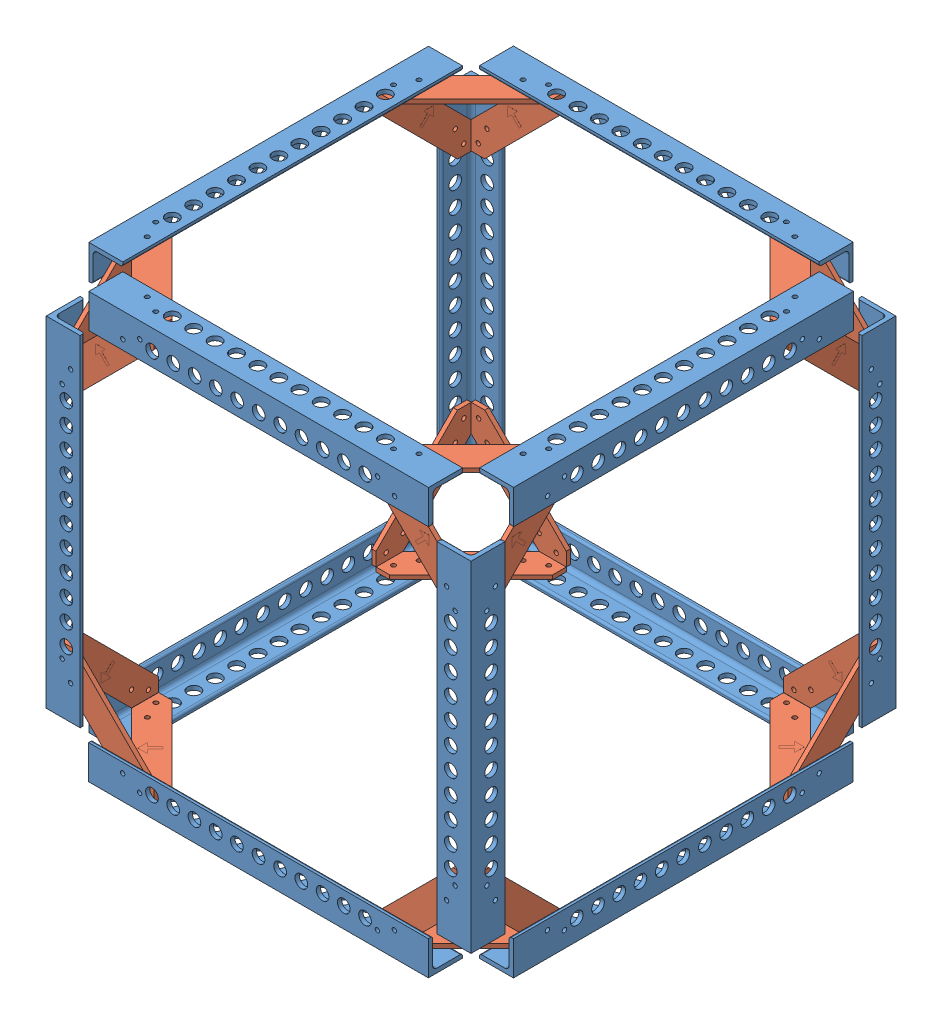
SolidWorks assembly Proof of Concept CAD 2 - Min Brackets, configuration Default. Lengths in mm.
Overall size (317.63 317.62 317.63).
38 component instances, 2 part files, 46 mates.
Components (placement in the parent):
- test assemby 1-1: test assemby 1 [Default] at (189.8318 11.2658 54.9643) size (317.51 25.4 317.63)
  - MOD Al L rod-4: MOD Al L rod [8982K401] at (158.011 130.5289 151.3983) size (25.4 25.4 254)
  - MOD Al L rod-5: MOD Al L rod [8982K401] at (11.9531 130.5289 5.2213) x (0 0 -1) z (1 0 0) size (25.4 25.4 254)
  - draft bracket-1: draft bracket [Default] at (164.361 121.0039 -1.0017) size (71.12 3.2 71.12)
  - MOD Al L rod-7: MOD Al L rod [8982K401] at (11.834 130.5289 297.4562) x (0 0 1) z (-1 0 0) size (25.4 25.4 254)
  - draft bracket-3: draft bracket [Default] at (164.234 121.0039 303.8062) x (0 0 1) z (-1 0 0) size (71.12 3.2 71.12)
  - MOD Al L rod-9: MOD Al L rod [8982K401] at (-134.0969 130.5289 151.2713) x (-1 0 0) z (0 0 -1) size (25.4 25.4 254)
  - draft bracket-6: draft bracket [Default] at (-140.4469 121.0039 -1.1287) x (0 0 -1) z (1 0 0) size (71.12 3.2 71.12)
  - draft bracket-7: draft bracket [Default] at (-140.4469 121.0039 303.6713) x (-1 0 0) z (0 0 -1) size (71.12 3.2 71.12)
- MOD Al L rod-1: MOD Al L rod [8982K401] at (55.6237 287.8447 352.4206) x (-1 0 0) z (0 -1 0) size (25.4 25.4 254)
- draft bracket-2: draft bracket [Default] at (49.2737 135.4447 361.9456) x (0 -1 0) z (1 0 0) size (71.12 3.2 71.12)
- draft bracket-3: draft bracket [Default] at (46.2099 135.5717 358.6357) x (0 0 1) z (0 1 0) size (71.12 3.2 71.12)
- draft bracket-4: draft bracket [Default] at (354.1928 135.4526 361.9456) x (1 0 0) z (0 1 0) size (71.12 3.2 71.12)
- draft bracket-5: draft bracket [Default] at (357.3678 135.4447 358.7706) x (0 -1 0) z (0 0 -1) size (71.12 3.2 71.12)
- MOD Al L rod-2: MOD Al L rod [8982K401] at (347.8428 287.8447 352.4206) x (0 0 1) z (0 -1 0) size (25.4 25.4 254)
- draft bracket-6: draft bracket [Default] at (49.3849 135.4447 50.6607) x (-1 0 0) z (0 1 0) size (71.12 3.2 71.12)
- draft bracket-7: draft bracket [Default] at (46.2099 135.4447 53.8357) x (0 -1 0) z (0 0 1) size (71.12 3.2 71.12)
- MOD Al L rod-3: MOD Al L rod [8982K401] at (55.7349 287.8447 60.1857) x (0 0 -1) z (0 -1 0) size (25.4 25.4 254)
- draft bracket-10: draft bracket [Default] at (357.3678 135.4447 53.8357) x (0 0 -1) z (0 1 0) size (71.12 3.2 71.12)
- draft bracket-11: draft bracket [Default] at (354.1928 135.4447 50.6607) x (0 -1 0) z (-1 0 0) size (71.12 3.2 71.12)
- MOD Al L rod-5: MOD Al L rod [8982K401] at (347.8428 287.8447 60.1857) x (1 0 0) z (0 -1 0) size (25.4 25.4 254)
- test assemby 1-2: test assemby 1 [Default] at (189.8397 564.5428 357.6419) x (1 0 0) z (0 0 -1) size (317.51 25.4 317.63)
  - MOD Al L rod-4: MOD Al L rod [8982K401] at (158.011 130.5289 151.3983) size (25.4 25.4 254)
  - MOD Al L rod-5: MOD Al L rod [8982K401] at (11.9531 130.5289 5.2213) x (0 0 -1) z (1 0 0) size (25.4 25.4 254)
  - draft bracket-1: draft bracket [Default] at (164.361 121.0039 -1.0017) size (71.12 3.2 71.12)
  - MOD Al L rod-7: MOD Al L rod [8982K401] at (11.834 130.5289 297.4562) x (0 0 1) z (-1 0 0) size (25.4 25.4 254)
  - draft bracket-3: draft bracket [Default] at (164.234 121.0039 303.8062) x (0 0 1) z (-1 0 0) size (71.12 3.2 71.12)
  - MOD Al L rod-9: MOD Al L rod [8982K401] at (-134.0969 130.5289 151.2713) x (-1 0 0) z (0 0 -1) size (25.4 25.4 254)
  - draft bracket-6: draft bracket [Default] at (-140.4469 121.0039 -1.1287) x (0 0 -1) z (1 0 0) size (71.12 3.2 71.12)
  - draft bracket-7: draft bracket [Default] at (-140.4469 121.0039 303.6713) x (-1 0 0) z (0 0 -1) size (71.12 3.2 71.12)
- draft bracket-13: draft bracket [Default] at (354.1928 440.2368 358.7706) x (1 0 0) z (0 -1 0) size (71.12 3.2 71.12)
- draft bracket-14: draft bracket [Default] at (354.1928 440.2526 358.6436) x (0 1 0) z (0 0 -1) size (71.12 3.2 71.12)
- draft bracket-15: draft bracket [Default] at (49.2737 440.2368 358.7706) x (0 0 1) z (0 -1 0) size (71.12 3.2 71.12)
- draft bracket-16: draft bracket [Default] at (49.2737 440.3638 358.7706) x (0 1 0) z (1 0 0) size (71.12 3.2 71.12)
- draft bracket-17: draft bracket [Default] at (49.2816 440.3638 50.6607) x (0 1 0) z (1 0 0) size (71.12 3.2 71.12)
- draft bracket-18: draft bracket [Default] at (354.1928 440.3638 53.8357) x (0 1 0) z (-1 0 0) size (71.12 3.2 71.12)
- draft bracket-19: draft bracket [Default] at (46.2099 440.2447 53.8357) x (0 0 -1) z (0 -1 0) size (71.12 3.2 71.12)
- draft bracket-20: draft bracket [Default] at (354.1928 440.2368 53.8357) x (0 0 -1) z (0 -1 0) size (71.12 3.2 71.12)
Mates (geometry in assembly coordinates):
- Coincident1: coincident aligned: circle of test assemby 1-1/MOD Al L rod-7; circle of draft bracket-2
- Coincident3: coincident aligned: line of test assemby 1-1/MOD Al L rod-7 through (74.6658 135.4447 361.9456) axis (1 0 0); line of draft bracket-2 through (100.0737 135.4447 361.9456) axis (1 0 0)
- Coincident4: coincident anti-aligned: circle of MOD Al L rod-1; circle of draft bracket-2
- Coincident6: coincident aligned: line of MOD Al L rod-1 through (49.2737 160.8447 361.9456) axis (0 1 0); line of draft bracket-2 through (49.2737 186.2447 361.9456) axis (0 1 0)
- Coincident7: coincident aligned: circle of test assemby 1-1/MOD Al L rod-9; circle of draft bracket-3
- Parallel1: parallel aligned: line of MOD Al L rod-1 through (46.0987 160.8447 358.7706) axis (0 1 0); line of draft bracket-3 through (46.2099 186.3717 358.6357) axis (0 1 0)
- Coincident13: coincident anti-aligned: circle of draft bracket-5; circle of MOD Al L rod-2
- Coincident14: coincident aligned: line of draft bracket-5 through (357.3678 186.2447 358.7706) axis (0 1 0); line of MOD Al L rod-2 through (357.3678 160.8447 358.7706) axis (0 1 0)
- Parallel2: parallel aligned: line of draft bracket-4 through (354.1928 186.2526 361.9456) axis (0 1 0); line of MOD Al L rod-2 through (354.1928 160.8447 361.9456) axis (0 1 0)
- Coincident15: coincident aligned: circle of draft bracket-4; circle of MOD Al L rod-2
- Coincident16: coincident aligned: line of test assemby 1-1/MOD Al L rod-4 through (357.3678 135.4447 333.3627) axis (0 0 -1); line of draft bracket-5 through (357.3678 135.4447 307.9706) axis (0 0 -1)
- Coincident17: coincident: circle of test assemby 1-1/MOD Al L rod-7; circle of draft bracket-4
- Parallel4: parallel anti-aligned: line of test assemby 1-1/MOD Al L rod-7 through (74.6658 135.4447 361.9456) axis (1 0 0); line of draft bracket-4 through (303.3928 135.4526 361.9456) axis (-1 0 0)
- Coincident19: coincident anti-aligned: circle of draft bracket-7; circle of MOD Al L rod-3
- Coincident20: coincident aligned: line of draft bracket-7 through (46.2099 186.2447 53.8357) axis (0 1 0); line of MOD Al L rod-3 through (46.2099 160.8447 53.8357) axis (0 1 0)
- Coincident21: coincident aligned: line of draft bracket-6 through (49.3849 186.2447 50.6607) axis (0 1 0); line of MOD Al L rod-3 through (49.3849 160.8447 50.6607) axis (0 1 0)
- Coincident23: coincident aligned: circle of draft bracket-6; circle of MOD Al L rod-3
- Coincident32: coincident anti-aligned: line of test assemby 1-1/MOD Al L rod-5 through (328.7849 135.4447 50.6607) axis (-1 0 0); line of draft bracket-6 through (100.1849 135.4447 50.6607) axis (1 0 0)
- Coincident33: coincident aligned: circle of test assemby 1-1/MOD Al L rod-9; circle of draft bracket-7
- Coincident34: coincident anti-aligned: circle of draft bracket-9; circle of MOD Al L rod-4
- Coincident35: coincident aligned: line of draft bracket-9 through (1439.6661 1201.1399 56.0831) axis (0 1 0); line of MOD Al L rod-4 through (1439.6661 1183.3599 56.0831) axis (0 1 0)
- Coincident36: coincident aligned: line of draft bracket-11 through (354.1928 186.2447 50.6607) axis (0 1 0); line of MOD Al L rod-5 through (354.1928 160.8447 50.6607) axis (0 1 0)
- Coincident37: coincident anti-aligned: circle of draft bracket-11; circle of MOD Al L rod-5
- Coincident38: coincident aligned: circle of draft bracket-10; circle of MOD Al L rod-5
- Coincident39: coincident aligned: line of draft bracket-10 through (357.3678 186.2447 53.8357) axis (0 1 0); line of MOD Al L rod-5 through (357.3678 160.8447 53.8357) axis (0 1 0)
- Coincident40: coincident anti-aligned: line of test assemby 1-1/MOD Al L rod-4 through (357.3678 135.4447 333.3627) axis (0 0 -1); line of draft bracket-10 through (357.3678 135.4447 104.6357) axis (0 0 1)
- Coincident41: coincident aligned: line of test assemby 1-1/MOD Al L rod-5 through (328.7849 135.4447 50.6607) axis (-1 0 0); line of draft bracket-11 through (303.3928 135.4447 50.6607) axis (-1 0 0)
- Coincident44: coincident anti-aligned: circle of MOD Al L rod-2; circle of draft bracket-13
- Coincident45: coincident anti-aligned: circle of test assemby 1-2/MOD Al L rod-5; circle of draft bracket-13
- Coincident46: coincident anti-aligned: line of MOD Al L rod-2 through (354.1928 160.8447 361.9456) axis (0 1 0); line of draft bracket-13 through (354.1928 389.4368 361.9456) axis (0 -1 0)
- Parallel5: parallel aligned: line of test assemby 1-2/MOD Al L rod-5 through (328.7928 440.3638 361.9456) axis (-1 0 0); line of draft bracket-13 through (303.3928 440.2368 361.9456) axis (-1 0 0)
- Coincident47: coincident anti-aligned: circle of MOD Al L rod-2; circle of draft bracket-14
- Parallel6: parallel anti-aligned: line of test assemby 1-2/MOD Al L rod-4 through (357.3757 440.3638 79.2436) axis (0 0 1); line of draft bracket-14 through (357.3678 440.2526 307.8436) axis (0 0 -1)
- Coincident52: coincident anti-aligned: line of test assemby 1-2/MOD Al L rod-5 through (328.7928 440.3638 361.9456) axis (-1 0 0); line of draft bracket-16 through (100.0737 440.3638 361.9456) axis (1 0 0)
- Coincident53: coincident anti-aligned: line of MOD Al L rod-1 through (49.2737 160.8447 361.9456) axis (0 1 0); line of draft bracket-16 through (49.2737 389.5638 361.9456) axis (0 -1 0)
- Coincident59: coincident aligned: line of test assemby 1-2/MOD Al L rod-9 through (46.2178 440.3638 333.3706) axis (0 0 -1); line of draft bracket-15 through (46.0987 440.2368 315.5906) axis (0 0 -1)
- Coincident62: coincident anti-aligned: circle of MOD Al L rod-1; circle of draft bracket-15
- Parallel12: parallel aligned: line of test assemby 1-2/MOD Al L rod-9 through (46.2178 440.3638 333.3706) axis (0 0 -1); line of draft bracket-15 through (46.0987 440.2368 307.9706) axis (0 0 -1)
- Coincident67: coincident aligned: circle of test assemby 1-2/MOD Al L rod-7; circle of draft bracket-17
- Parallel13: parallel anti-aligned: line of MOD Al L rod-3 through (49.3849 160.8447 50.6607) axis (0 1 0); line of draft bracket-17 through (49.2816 389.5638 50.6607) axis (0 -1 0)
- Coincident73: coincident anti-aligned: line of test assemby 1-2/MOD Al L rod-7 through (74.6737 440.3638 50.6607) axis (1 0 0); line of draft bracket-18 through (303.3928 440.3638 50.6607) axis (-1 0 0)
- Coincident74: coincident anti-aligned: line of MOD Al L rod-5 through (354.1928 160.8447 50.6607) axis (0 1 0); line of draft bracket-18 through (354.1928 389.5638 50.6607) axis (0 -1 0)
- Coincident79: coincident aligned: circle of MOD Al L rod-3; circle of draft bracket-19
- Parallel15: parallel anti-aligned: line of test assemby 1-2/MOD Al L rod-9 through (46.2178 440.3638 333.3706) axis (0 0 -1); line of draft bracket-19 through (46.2099 440.2447 104.6357) axis (0 0 1)
- Coincident83: coincident anti-aligned: circle of MOD Al L rod-5; circle of draft bracket-20
- Parallel16: parallel aligned: line of test assemby 1-2/MOD Al L rod-4 through (357.3757 440.3638 79.2436) axis (0 0 1); line of draft bracket-20 through (357.3678 440.2368 104.6357) axis (0 0 1)
